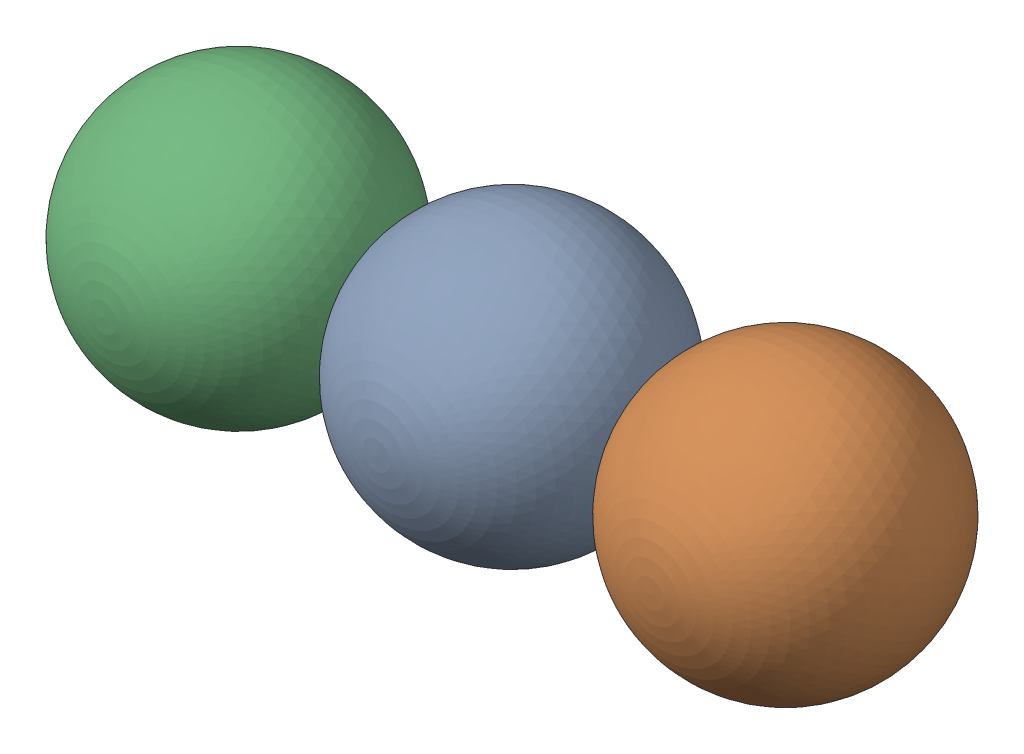
SolidWorks assembly Assem6, configuration Default. Lengths in mm.
Overall size (179.8 66.94 60.57).
3 component instances, 1 part files, 3 mates.
Components (placement in the parent):
- secondhalfpart1-13: secondhalfpart1 [Default] at (-26.1588 7.5409 60) size (60 60 60)
- secondhalfpart1-14: secondhalfpart1 [Default] at (33.74 11.0133 59.7154) size (60 60 60)
- secondhalfpart1-15: secondhalfpart1 [Default] at (-86.0575 4.0685 60.2846) size (60 60 60)
Mates (geometry in assembly coordinates):
- Tangent7: tangent anti-aligned: sphere of secondhalfpart1-13; sphere of secondhalfpart1-15
- Tangent8: tangent anti-aligned: sphere of secondhalfpart1-13; sphere of secondhalfpart1-14
- Distance9: distance = 60 mm anti-aligned: sphere of secondhalfpart1-15; sphere of secondhalfpart1-14
